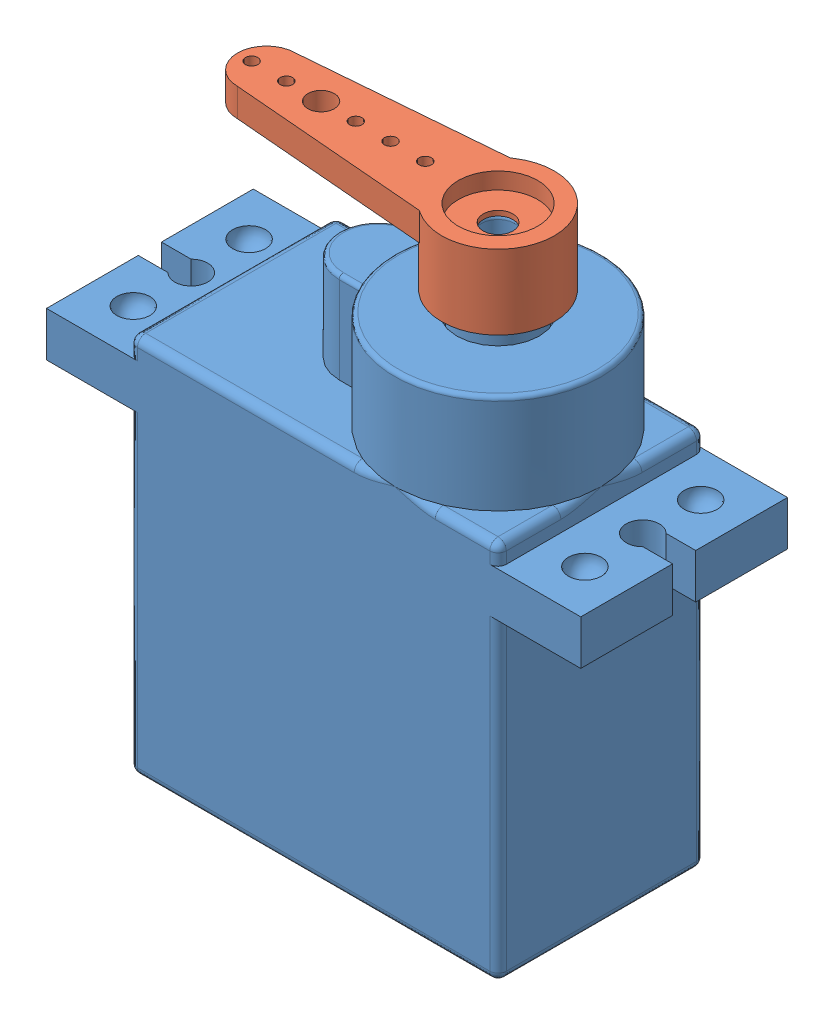
SolidWorks assembly Cubesat_SG90, configuration Výchozí. Lengths in mm.
2 component instances, 2 part files, 6 mates.
Components (placement in the parent):
- Cubesat_SG90_Body-1: Cubesat_SG90_Body [Výchozí] at (-8.8 11.5 6.25) x (1 0 0) z (0 -1 0) size (32.3 12.5 33.4)
- Cubesat_SG90_Moving_Part-1: Cubesat_SG90_Moving_Part [Výchozí] at (7.25 18.7 0) x (-1 0 0) z (0 1 0) size (19.15 6.8 4.5)
Mates (geometry in assembly coordinates):
- Sjednocená3: coincident anti-aligned: plane of Cubesat_SG90_Body-1 through (-8.8 0 6.25) normal (0 -1 0)
- Sjednocená4: coincident aligned: plane of Cubesat_SG90_Body-1 through (-8.8 11.5 0) normal (0 0 1)
- Sjednocená5: coincident anti-aligned: plane of Cubesat_SG90_Body-1 through (0 11.5 6.25) normal (-1 0 0)
- Soustředná1: concentric aligned: cylinder of Cubesat_SG90_Body-1 through (7.25 21.9 0) axis (0 -1 0) radius 2.25; cylinder of Cubesat_SG90_Moving_Part-1 through (7.25 21.9 0) axis (0 -1 0) radius 2.25
- Sjednocená6: coincident anti-aligned: plane of Cubesat_SG90_Body-1 through (7.25 21.9 0) normal (0 1 0); plane of Cubesat_SG90_Moving_Part-1 through (7.25 21.9 0) normal (0 -1 0)
- Mezní úhel2: limit planar angle = 3.141593 rad anti-aligned: plane of Cubesat_SG90_Moving_Part-1 through (7.25 18.7 0) normal (0 0 1)
